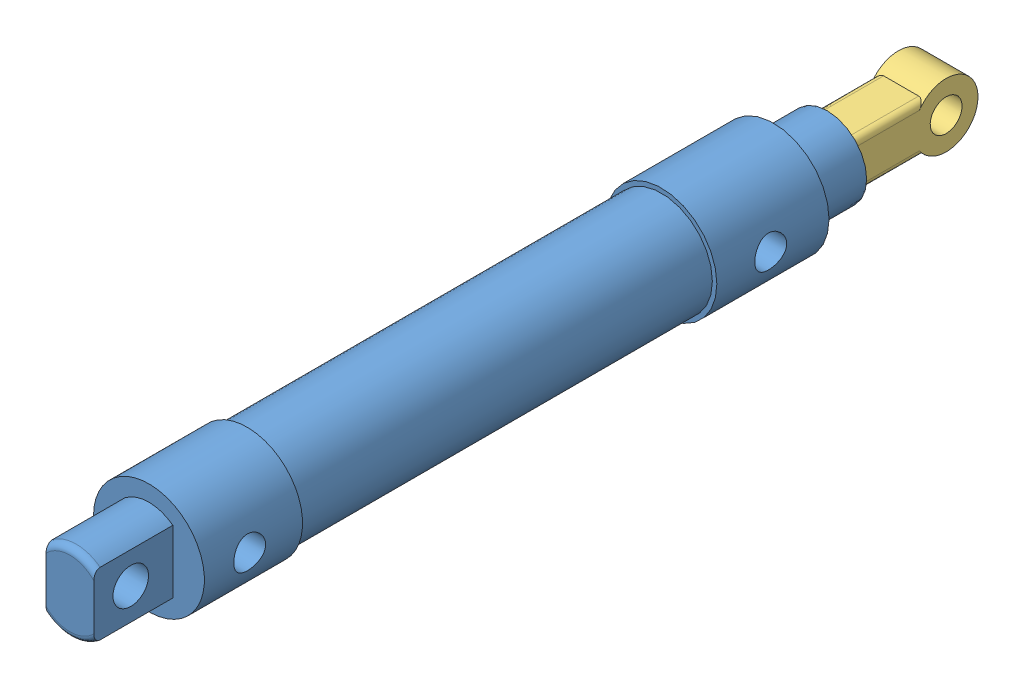
SolidWorks assembly AirCylinder_0.75x2in_Assem, configuration Default. Lengths in mm.
Overall size (22.1 22.1 176.32).
3 component instances, 3 part files, 5 mates.
Components (placement in the parent):
- AirCylinder_0.75x2in-1: AirCylinder_0.75x2in [Default] at origin size (22.1 22.1 151.02)
- AirCylinder_Rod-1: AirCylinder_Rod [Default] at (0 0 17.78) x (0.870942 -0.491386 0) z (0 0 -1) size (6.35 6.35 63.5)
- Clevas-1: Clevas [Default] at (-4.7625 0 -51.9685) x (0 0 -1) z (0 -1 0) size (25.3 9.53 12.7)
Mates (geometry in assembly coordinates):
- Concentric1: concentric anti-aligned: cylinder of AirCylinder_0.75x2in-1 through (0 0 91.948) axis (0 0 -1) radius 3.175; cylinder of AirCylinder_Rod-1 through (0 0 -45.72) axis (0 0 1) radius 3.175
- LimitDistance1: limit distance = 12.7 mm aligned: plane of AirCylinder_0.75x2in-1 through (0 0 -33.02) normal (0 0 -1); plane of AirCylinder_Rod-1 through (0 0 -45.72) normal (0 0 -1)
- Concentric2: concentric aligned: cylinder of AirCylinder_Rod-1 through (0 0 -45.72) axis (0 0 1) radius 3.175; cylinder of Clevas-1 through (0 0 -45.72) axis (0 0 1) radius 3.175
- Coincident1: coincident anti-aligned: plane of AirCylinder_Rod-1 through (0 0 -45.72) normal (0 0 -1); plane of Clevas-1 through (0 0 -45.72) normal (0 0 1)
- Parallel1: parallel anti-aligned: plane of AirCylinder_0.75x2in-1 through (-4.7625 -6.2704 117.856) normal (-1 0 0); plane of Clevas-1 through (4.7625 0 -51.9685) normal (1 0 0)
